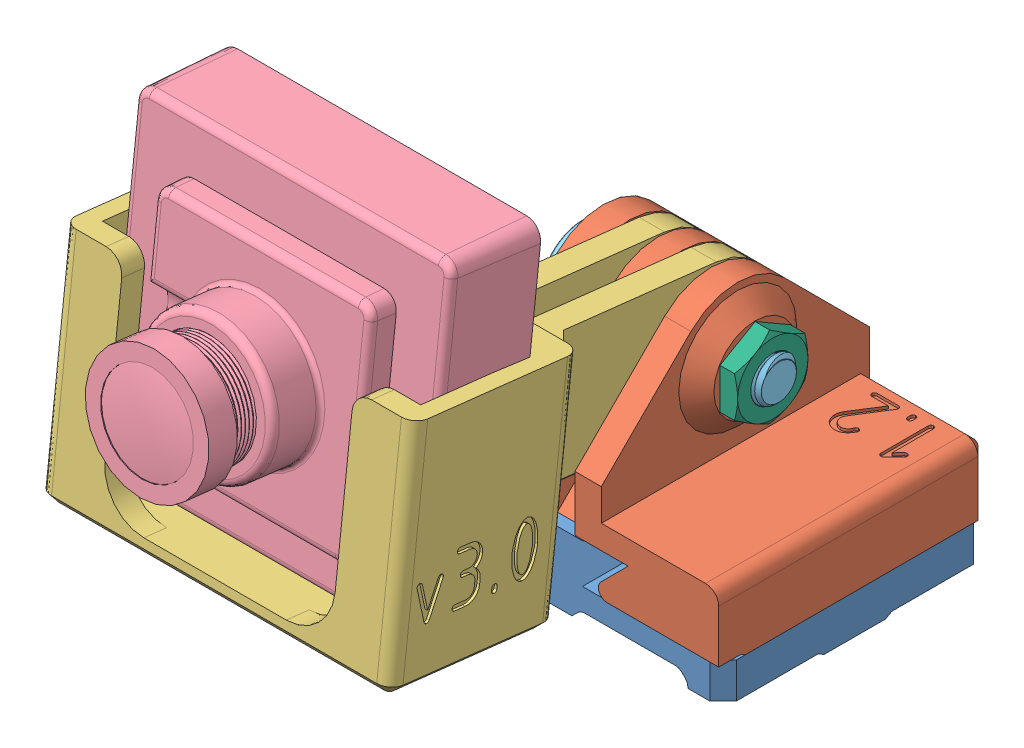
SolidWorks assembly CAM, configuration Default. Lengths in mm.
Overall size (42 66.17 76.88).
6 component instances, 6 part files, 24 mates.
Components (placement in the parent):
- twistBracket_v3-2: twistBracket_v3 [Default] x (0 0 1) z (-1 0 0) size (30 17.2 42)
- cameraJoint-2: cameraJoint [Default] at (0 3.8 -15) size (42 23.8 30.5)
- cameraBracket_v3-2: cameraBracket_v3 [Default] at (0 19.8 0) x (0 0.99364 -0.112602) z (1 0 0) size (26 59 40)
- camera-2: camera [Default] at (0 36.5391 34.8367) x (1 0 0) z (0 0.112602 0.99364) size (36.42 36.42 31.72)
- screw_m5x20-1: screw_m5x20 [screw_20mm] at (0.4 19.8 0) x (0 0 -1) z (-1 0 0) size (10 10 24.19)
- nut_m5-1: nut_m5 [nut_m5] at (9.65 19.8 0) x (0 0 -1) z (-1 0 0) size (8 9.24 4.46)
Mates (geometry in assembly coordinates):
- Concentric1: concentric anti-aligned: cylinder of SqCamBrk-1 through (54.3499 13.5 7.4999) axis (0 1 0) radius 2.65; cylinder of goProPlain v1.0-1 through (38.8 7.5 23) axis (0 -1 0) radius 2.7
- Coincident13: coincident anti-aligned: plane of SqCamBrk-1 through (61.4943 19.5 -0.3395) normal (0 1 0); plane of goProPlain v1.0-1 through (46.3 -1.5 30.5) normal (0 -1 0)
- Coincident20: coincident anti-aligned: plane of SqCamBrk-1 through (8.8507 2.9 34.1369) normal (0.046338 0 0.998926); plane of camera-2 through (0 36.5391 34.8367) normal (0 -0.112602 -0.99364)
- Parallel5: parallel aligned: plane of SqCamBrk-1 through (54.3499 28.5 7.4999) normal (0.998926 0 -0.046338); plane of camera-2 through (0 36.5391 34.8367) normal (0 0.99364 -0.112602)
- Coincident25: coincident: plane of SqCamBrk-1 through (8.8507 39.1 34.1369) normal (0 -1 0); line of camera-2 through (-18.2119 52.8845 32.9844) axis (0 -0.99364 0.112602)
- Coincident26: coincident aligned: plane of SqCamBrk-1 through (48.8558 13.5 7.7548) normal (0.998926 0 -0.046338); plane of camera-2 through (0 18.4431 36.8874) normal (0 0.99364 -0.112602)
- Concentric4: concentric anti-aligned: cylinder of goProPlain v1.0-1 through (38.8 7.5 23) axis (0 -1 0) radius 2.7; cylinder of cameraBracket_v3-2 through (7.5 19.8 0) axis (-1 0 0) radius 2.65
- Coincident31: coincident aligned: plane of twistBracket_v3-2 through (0 0 0) normal (0 1 0)
- Coincident37: coincident aligned: plane of twistBracket_v3-2 through (-21 0 -15) normal (0 0 -1); plane of DoveTailF_gpB-2 through (0 3.8 -15) normal (0 0 -1)
- Concentric5: concentric: circle of nut m5-1; line of cameraJoint-2 through (15 19.8 0) axis (-1 0 0)
- Coincident47: coincident: plane of nut m5-1 through (7.65 15.1854 0.1965) normal (-1 0 0); plane of cameraJoint-2 through (7.65 3.8 -15) normal (1 0 0)
- Coincident51: coincident aligned: line of cameraBracket_v3-2 through (22 19.8 0) axis (-1 0 0); line of screw_m5x20-1 through (13.9048 19.8 0) axis (-1 0 0)
- Coincident52: coincident anti-aligned: plane of cameraJoint-2 through (-7.65 27.3 -15) normal (-1 0 0); plane of screw_m5x20-1 through (-7.65 23.6864 0) normal (1 0 0)
- Coincident54: coincident aligned: plane of twistBracket_v3-2 through (0 0 0) normal (0 0 1)
- Coincident55: coincident anti-aligned: plane of twistBracket_v3-2 through (0 0 0) normal (-1 0 0)
- Coincident56: coincident anti-aligned: plane of twistBracket_v3-2 through (-21 3.5 -15) normal (0 1 0); plane of cameraJoint-2 through (-21 3.5 -15) normal (0 -1 0)
- Coincident57: coincident aligned: plane of cameraJoint-2 through (0 3.8 -15) normal (1 0 0)
- Coincident58: coincident aligned: line of cameraJoint-2 through (15 19.8 0) axis (-1 0 0); line of cameraBracket_v3-2 through (22 19.8 0) axis (-1 0 0)
- Coincident59: coincident aligned: plane of cameraJoint-2 through (0 3.8 -15) normal (1 0 0); plane of cameraBracket_v3-2 through (0 19.8 0) normal (1 0 0)
- Coincident60: coincident anti-aligned: plane of cameraBracket_v3-2 through (18.1 -22.4778 41.5247) normal (0 0.112602 0.99364); plane of camera-2 through (0 36.5391 34.8367) normal (0 -0.112602 -0.99364)
- Coincident61: coincident aligned: plane of cameraBracket_v3-2 through (0 19.8 0) normal (1 0 0); plane of camera-2 through (0 36.5391 34.8367) normal (1 0 0)
- Coincident62: coincident aligned: plane of cameraBracket_v3-2 through (0 32.4292 -1.4312) normal (0 0.99364 -0.112602); plane of camera-2 through (0 36.5391 34.8367) normal (0 0.99364 -0.112602)
- Parallel7: parallel anti-aligned: plane of cameraJoint-2 through (0 3.8 -15) normal (0 1 0); plane of screw_m5x20-1 through (0.4 19.8 0) normal (0 -1 0)
- Parallel8: parallel anti-aligned: plane of cameraJoint-2 through (0 3.8 -15) normal (0 0 1); plane of nut_m5-1
